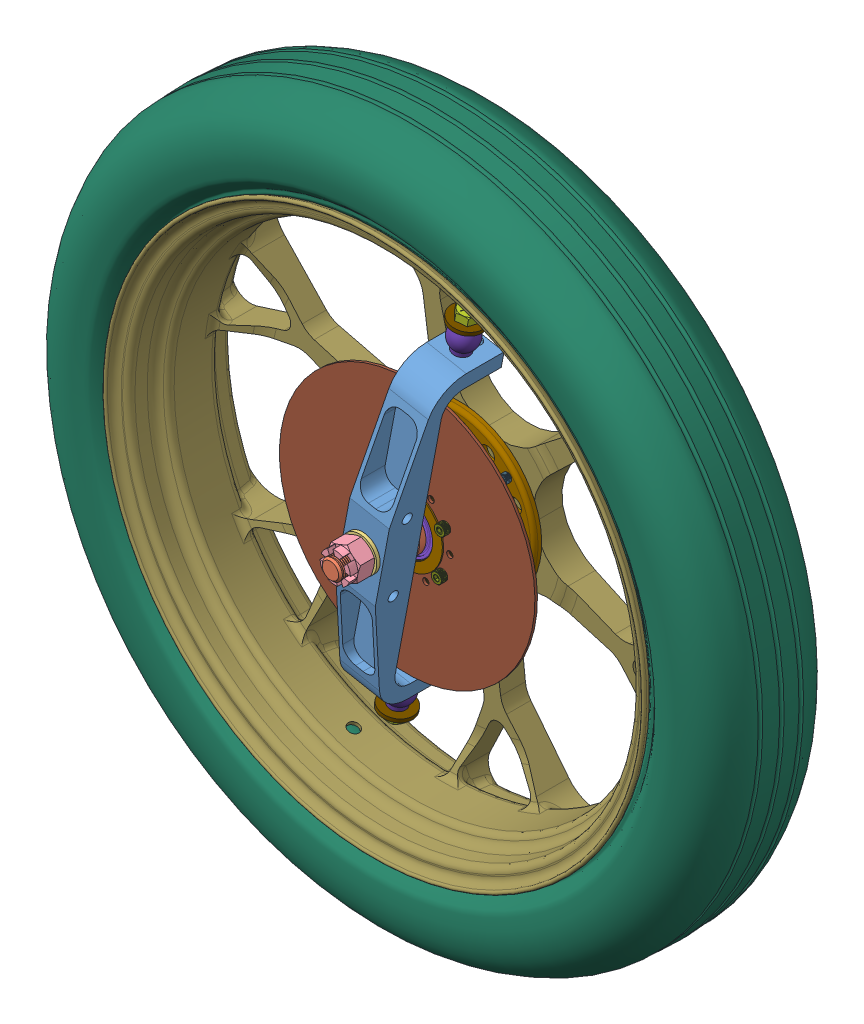
SolidWorks assembly SpindleAssy, configuration Default. Lengths in mm.
Overall size (616.2 616.2 145).
36 component instances, 18 part files, 73 mates.
Components (placement in the parent):
- Knuckle-1: Knuckle [Default] at (82.0121 130.0239 204.0915) size (78.12 253.33 73.5)
- Spindle_Light-1: Spindle_Light [Default] at (82.0121 130.0239 204.0915) x (0 0 -1) z (0.185408 0.982662 0) size (140.5 34 30)
- M16 98688A121_General Purpose Zinc-Plated Steel Washer-1: M16 98688A121_General Purpose Zinc-Plated Steel Washer [98688A121] at (82.0121 130.0239 232.5915) x (0.99983 -0.018445 0) z (0 0 1) size (28 28 2.7)
- M16x1-5 93760A128_Steel Locknut for Use with Cotter Pins-1: M16x1-5 93760A128_Steel Locknut for Use with Cotter Pins [93760A128] at (82.0121 130.0239 254.2915) x (0.982886 -0.184217 0) z (0 0 1) size (24 27.71 19.76)
- M14 98689A119_General Purpose 18-8 Stainless Steel Washer-1: M14 98689A119_General Purpose 18-8 Stainless Steel Washer [98689A119] at (82.0121 130.0239 138.2415) size (24 24 2.7)
- M14x1-5 93760A127_Steel Locknut for Use with Cotter Pins-1: M14x1-5 93760A127_Steel Locknut for Use with Cotter Pins [93760A127] at (82.0121 130.0239 120.8915) x (-0.661913 -0.74958 0) z (0 0 -1) size (22 25.4 16.76)
- 91257A659_Zinc Yellow-Chromate Plated Hex Head Screw-2: 91257A659_Zinc Yellow-Chromate Plated Hex Head Screw [91257A659] at (58.1191 3.3909 177.4439) x (0.185408 0.982662 0) z (0.110595 -0.020867 0.993646) size (57.6 16.5 14.29)
- 91257A659_Zinc Yellow-Chromate Plated Hex Head Screw-3: 91257A659_Zinc Yellow-Chromate Plated Hex Head Screw [91257A659] at (105.9051 256.6568 177.4439) x (-0.185408 -0.982662 0) z (-0.685297 0.129301 0.716693) size (57.6 16.5 14.29)
- SKF_6004-2Z.stp-1: SKF_6004-2Z.stp [Default] at (82.0121 130.0239 185.0915) x (0 0 1) z (-0.58163 0.813454 0) size (12 42 42)
- Hub5-16-1: Hub5-16 [Default] at (82.0121 130.0239 173.6746) x (-0.944813 0.32761 0) z (0.32761 0.944813 0) size (130 85 130)
- SKF_6003-2Z.stp-1: SKF_6003-2Z.stp [Default] at (82.0121 130.0239 149.5915) x (0 0 -1) z (0.973183 -0.230032 0) size (10 35 35)
- BasicBrakeDisc-1: BasicBrakeDisc [Default] at (82.0121 130.0239 195.0915) x (0.071911 0.997411 0) z (0 0 1) size (190.5 190.5 3.17)
- rimmachined v13.2-1: rimmachined v13.2 [Default] at (82.0121 130.0239 177.3915) x (0 0 -1) z (-0.981935 -0.189217 0) size (93.59 431.57 431.57)
- 92415A381_Zinc-Plated Steel Unthreaded Spacer-2: 92415A381_Zinc-Plated Steel Unthreaded Spacer [92415A381] at (71.0682 186.982 155.2387) size (7.94 7.94 7.21)
- 92415A381_Zinc-Plated Steel Unthreaded Spacer-3: 92415A381_Zinc-Plated Steel Unthreaded Spacer [92415A381] at (27.2129 149.0252 155.2387) size (7.94 7.94 7.21)
- 92415A381_Zinc-Plated Steel Unthreaded Spacer-4: 92415A381_Zinc-Plated Steel Unthreaded Spacer [92415A381] at (38.1569 92.0671 155.2387) size (7.94 7.94 7.21)
- 92415A381_Zinc-Plated Steel Unthreaded Spacer-5: 92415A381_Zinc-Plated Steel Unthreaded Spacer [92415A381] at (92.956 73.0657 155.2387) size (7.94 7.94 7.21)
- 92415A381_Zinc-Plated Steel Unthreaded Spacer-6: 92415A381_Zinc-Plated Steel Unthreaded Spacer [92415A381] at (136.8113 111.0225 155.2387) size (7.94 7.94 7.21)
- 92415A381_Zinc-Plated Steel Unthreaded Spacer-7: 92415A381_Zinc-Plated Steel Unthreaded Spacer [92415A381] at (125.8674 167.9807 155.2387) size (7.94 7.94 7.21)
- 8-32x3-8 92196A192_18-8 Stainless Steel Socket Head Screw-1: 8-32x3-8 92196A192_18-8 Stainless Steel Socket Head Screw [92196A192] at (92.956 73.0657 158.4118) size (6.85 6.85 14.15)
- 8-32x3-8 92196A192_18-8 Stainless Steel Socket Head Screw-2: 8-32x3-8 92196A192_18-8 Stainless Steel Socket Head Screw [92196A192] at (38.1569 92.0671 158.4118) size (6.85 6.85 14.15)
- 8-32x3-8 92196A192_18-8 Stainless Steel Socket Head Screw-3: 8-32x3-8 92196A192_18-8 Stainless Steel Socket Head Screw [92196A192] at (136.8113 111.0225 158.4118) size (6.85 6.85 14.15)
- 8-32x3-8 92196A192_18-8 Stainless Steel Socket Head Screw-4: 8-32x3-8 92196A192_18-8 Stainless Steel Socket Head Screw [92196A192] at (125.8674 167.9807 158.4118) size (6.85 6.85 14.15)
- 8-32x3-8 92196A192_18-8 Stainless Steel Socket Head Screw-5: 8-32x3-8 92196A192_18-8 Stainless Steel Socket Head Screw [92196A192] at (71.0682 186.982 158.4118) size (6.85 6.85 14.15)
- 8-32x3-8 92196A192_18-8 Stainless Steel Socket Head Screw-6: 8-32x3-8 92196A192_18-8 Stainless Steel Socket Head Screw [92196A192] at (27.2129 149.0252 158.4118) size (6.85 6.85 14.15)
- Michelin Tire-1: Michelin Tire [Default] at (82.0121 130.0239 177.3915) x (0 0 1) z (-0.993534 -0.113534 0) size (101.13 556.61 556.61)
- M5x10 91290A224_Alloy Steel Socket Head Screw-1: M5x10 91290A224_Alloy Steel Socket Head Screw [91290A224] at (84.4571 163.9358 194.5915) x (0.901899 0.431946 0) z (0 0 1) size (8.5 8.5 15.31)
- M5x10 91290A224_Alloy Steel Socket Head Screw-2: M5x10 91290A224_Alloy Steel Socket Head Screw [91290A224] at (53.866 149.0973 194.5915) x (-0.609316 -0.792927 0) z (0 0 1) size (8.5 8.5 15.31)
- M5x10 91290A224_Alloy Steel Socket Head Screw-3: M5x10 91290A224_Alloy Steel Socket Head Screw [91290A224] at (112.6032 144.8625 194.5915) x (0.740699 0.671837 0) z (0 0 1) size (8.5 8.5 15.31)
- M5x10 91290A224_Alloy Steel Socket Head Screw-4: M5x10 91290A224_Alloy Steel Socket Head Screw [91290A224] at (110.1583 110.9505 194.5915) x (-0.161403 -0.986889 0) z (0 0 1) size (8.5 8.5 15.31)
- M5x10 91290A224_Alloy Steel Socket Head Screw-5: M5x10 91290A224_Alloy Steel Socket Head Screw [91290A224] at (51.421 115.1853 194.5915) x (0.079005 -0.996874 0) z (0 0 1) size (8.5 8.5 15.31)
- M5x10 91290A224_Alloy Steel Socket Head Screw-6: M5x10 91290A224_Alloy Steel Socket Head Screw [91290A224] at (79.5671 96.1119 194.5915) x (-0.159143 -0.987256 0) z (0 0 1) size (8.5 8.5 15.31)
- BallSuper-Swivel  Joint Rod End6960T231_-1: BallSuper-Swivel  Joint Rod End6960T231_ [6960T231] at (75.3125 -8.1245 178.3098) x (-0.044663 0.008427 0.998967) z (-0.185408 -0.982662 0) size (20.64 20.64 22.23)
- BallSuper-Swivel  Joint Rod End6960T231_-2: BallSuper-Swivel  Joint Rod End6960T231_ [6960T231] at (109.0836 264.3285 196.4178) x (0.978736 -0.184667 -0.089292) z (0.185408 0.982662 0) size (20.64 20.64 22.23)
- 3-8 98029A046_Black-Oxide Steel Oversized Washer-1: 3-8 98029A046_Black-Oxide Steel Oversized Washer [98029A046] at (54.2751 -16.9823 177.4439) x (0.965511 -0.182172 -0.186017) z (0.185408 0.982662 0) size (25.4 25.4 2.98)
- 3-8 98029A046_Black-Oxide Steel Oversized Washer-2: 3-8 98029A046_Black-Oxide Steel Oversized Washer [98029A046] at (109.7491 277.0301 177.4439) x (0.965511 -0.182172 -0.186017) z (0.185408 0.982662 0) size (25.4 25.4 2.98)
Mates (geometry in assembly coordinates):
- Coincident1: coincident anti-aligned: circle of Knuckle-1; circle of Spindle_Light-1
- Concentric1: concentric aligned: circle of Knuckle-1; circle of M16 98688A121_General Purpose Zinc-Plated Steel Washer-1
- Concentric2: concentric aligned: circle of M16 98688A121_General Purpose Zinc-Plated Steel Washer-1; circle of M16x1-5 93760A128_Steel Locknut for Use with Cotter Pins-1
- Coincident2: coincident anti-aligned: plane of Knuckle-1 through (82.0121 130.0239 232.5915) normal (0 0 1); plane of M16 98688A121_General Purpose Zinc-Plated Steel Washer-1 through (82.0121 130.0239 232.5915) normal (0 0 -1)
- Coincident3: coincident anti-aligned: plane of M16 98688A121_General Purpose Zinc-Plated Steel Washer-1 through (82.0121 130.0239 235.2915) normal (0 0 1); plane of M16x1-5 93760A128_Steel Locknut for Use with Cotter Pins-1 through (84.5647 143.6431 235.2915) normal (0 0 -1)
- Parallel1: parallel aligned: plane of Spindle_Light-1 through (82.0121 130.0239 258.0915) normal (0 0 1); plane of M16x1-5 93760A128_Steel Locknut for Use with Cotter Pins-1 through (82.0121 130.0239 248.2915) normal (0 0 1)
- Concentric3: concentric anti-aligned: circle of M14 98689A119_General Purpose 18-8 Stainless Steel Washer-1; circle of M14x1-5 93760A127_Steel Locknut for Use with Cotter Pins-1
- Coincident5: coincident anti-aligned: plane of M14 98689A119_General Purpose 18-8 Stainless Steel Washer-1 through (82.0121 130.0239 136.8915) normal (0 0 -1); plane of M14x1-5 93760A127_Steel Locknut for Use with Cotter Pins-1 through (75.0117 150.8804 136.8915) normal (0 0 1)
- Concentric4: concentric anti-aligned: circle of Spindle_Light-1; circle of M14 98689A119_General Purpose 18-8 Stainless Steel Washer-1
- Perpendicular1: perpendicular: line of Knuckle-1 through (84.6232 230.1587 204.0915) axis (-0.185408 -0.982662 0); line of Spindle_Light-1 through (76.9319 146.2471 204.0915) axis (0.982662 -0.185408 0)
- Concentric5: concentric aligned: circle of Knuckle-1; circle of Super-Swivel Ball Joint Ball End2-1
- Coincident7: coincident anti-aligned: plane of Knuckle-1 through (89.6292 256.6906 232.5915) normal (0.185408 0.982662 0); plane of Super-Swivel Ball Joint Ball End2-1 through (107.5018 254.0508 172.0915) normal (-0.20131 -0.979528 0)
- Concentric6: concentric anti-aligned: circle of Knuckle-1; circle of Super-Swivel Ball Joint Ball End2-2
- Coincident8: coincident anti-aligned: plane of Knuckle-1 through (74.395 3.3572 232.5915) normal (-0.185408 -0.982662 0); plane of Super-Swivel Ball Joint Ball End2-2 through (56.5224 5.997 172.0915) normal (0.20131 0.979528 0)
- Coincident11: coincident anti-aligned: circle of Knuckle-1; circle of SteerArm-1
- Coincident12: coincident anti-aligned: circle of Knuckle-1; circle of SteerArm-1
- Concentric7: concentric anti-aligned: circle of Spindle_Light-1; circle of SKF_6004-2Z.stp-1
- Coincident13: coincident anti-aligned: plane of Spindle_Light-1 through (70.2202 132.2488 197.0915) normal (0 0 -1); plane of SKF_6004-2Z.stp-1 through (90.6347 136.1891 197.0915) normal (0 0 1)
- Coincident14: coincident anti-aligned: plane of SKF_6004-2Z.stp-1 through (98.6066 141.8891 185.0915) normal (0 0 -1); plane of Hub5-16-1 through (64.0607 136.2485 185.0915) normal (0 0 1)
- Concentric8: concentric aligned: cylinder of SKF_6004-2Z.stp-1 through (82.0121 130.0239 235.0915) axis (0 0 1) radius 21; cylinder of Hub5-16-1 through (82.0121 130.0239 1099.7023) axis (0 0 1) radius 21
- Concentric9: concentric anti-aligned: cylinder of Hub5-16-1 through (82.0121 130.0239 1099.7023) axis (0 0 1) radius 17.5; cylinder of SKF_6003-2Z.stp-1 through (82.0121 130.0239 99.5915) axis (0 0 -1) radius 17.5
- Coincident15: coincident anti-aligned: plane of Hub5-16-1 through (67.3675 135.1018 149.5915) normal (0 0 -1); plane of SKF_6003-2Z.stp-1 through (85.9687 146.7626 149.5915) normal (0 0 1)
- Coincident16: coincident anti-aligned: plane of M14 98689A119_General Purpose 18-8 Stainless Steel Washer-1 through (82.0121 130.0239 139.5915) normal (0 0 1); plane of SKF_6003-2Z.stp-1 through (84.0364 138.5879 139.5915) normal (0 0 -1)
- Concentric10: concentric aligned: circle of Hub5-16-1; circle of BasicBrakeDisc-1
- Coincident18: coincident anti-aligned: plane of Hub5-16-1 through (54.6125 139.5246 195.0915) normal (0 0 1); plane of BasicBrakeDisc-1 through (82.0121 130.0239 195.0915) normal (0 0 -1)
- Concentric11: concentric anti-aligned: cylinder of Hub5-16-1 through (82.0121 130.0239 1099.7023) axis (0 0 1) radius 47; cylinder of rimmachined v13.2-1 through (82.0121 130.0239 168.2915) axis (0 0 -1) radius 47.005
- Coincident19: coincident aligned: circle of Hub5-16-1; circle of 92415A381_Zinc-Plated Steel Unthreaded Spacer-5
- Coincident20: coincident aligned: circle of Hub5-16-1; circle of 92415A381_Zinc-Plated Steel Unthreaded Spacer-4
- Coincident21: coincident aligned: circle of Hub5-16-1; circle of 92415A381_Zinc-Plated Steel Unthreaded Spacer-3
- Coincident22: coincident aligned: circle of Hub5-16-1; circle of 92415A381_Zinc-Plated Steel Unthreaded Spacer-2
- Coincident23: coincident aligned: circle of Hub5-16-1; circle of 92415A381_Zinc-Plated Steel Unthreaded Spacer-7
- Coincident24: coincident aligned: circle of Hub5-16-1; circle of 92415A381_Zinc-Plated Steel Unthreaded Spacer-6
- Concentric121: concentric anti-aligned: cylinder of Hub5-16-1 through (92.956 73.0657 151.0915) axis (0 0 1) radius 2.15; cylinder of 8-32x3-8 92196A192_18-8 Stainless Steel Socket Head Screw-1 through (92.956 73.0657 151.5665) axis (0 0 -1) radius 2.0828
- Coincident251: coincident anti-aligned: plane of Hub5-16-1 through (23.4337 150.3357 161.0915) normal (0 0 1); plane of 8-32x3-8 92196A192_18-8 Stainless Steel Socket Head Screw-1 through (89.6985 73.0657 161.0915) normal (0 0 -1)
- Concentric131: concentric anti-aligned: cylinder of Hub5-16-1 through (38.1569 92.0671 151.0915) axis (0 0 1) radius 2.15; cylinder of 8-32x3-8 92196A192_18-8 Stainless Steel Socket Head Screw-2 through (38.1569 92.0671 151.5665) axis (0 0 -1) radius 2.0828
- Coincident261: coincident anti-aligned: plane of Hub5-16-1 through (23.4337 150.3357 161.0915) normal (0 0 1); plane of 8-32x3-8 92196A192_18-8 Stainless Steel Socket Head Screw-2 through (34.8993 92.0671 161.0915) normal (0 0 -1)
- Concentric141: concentric anti-aligned: cylinder of Hub5-16-1 through (136.8113 111.0225 151.0915) axis (0 0 1) radius 2.15; cylinder of 8-32x3-8 92196A192_18-8 Stainless Steel Socket Head Screw-3 through (136.8113 111.0225 151.5665) axis (0 0 -1) radius 2.0828
- Coincident271: coincident anti-aligned: plane of Hub5-16-1 through (23.4337 150.3357 161.0915) normal (0 0 1); plane of 8-32x3-8 92196A192_18-8 Stainless Steel Socket Head Screw-3 through (133.5537 111.0225 161.0915) normal (0 0 -1)
- Concentric151: concentric anti-aligned: cylinder of Hub5-16-1 through (125.8674 167.9807 151.0915) axis (0 0 1) radius 2.15; cylinder of 8-32x3-8 92196A192_18-8 Stainless Steel Socket Head Screw-4 through (125.8674 167.9807 151.5665) axis (0 0 -1) radius 2.0828
- Coincident281: coincident anti-aligned: plane of Hub5-16-1 through (23.4337 150.3357 161.0915) normal (0 0 1); plane of 8-32x3-8 92196A192_18-8 Stainless Steel Socket Head Screw-4 through (122.6098 167.9807 161.0915) normal (0 0 -1)
- Concentric161: concentric anti-aligned: cylinder of Hub5-16-1 through (71.0682 186.982 151.0915) axis (0 0 1) radius 2.15; cylinder of 8-32x3-8 92196A192_18-8 Stainless Steel Socket Head Screw-5 through (71.0682 186.982 151.5665) axis (0 0 -1) radius 2.0828
- Coincident291: coincident anti-aligned: plane of Hub5-16-1 through (23.4337 150.3357 161.0915) normal (0 0 1); plane of 8-32x3-8 92196A192_18-8 Stainless Steel Socket Head Screw-5 through (67.8106 186.982 161.0915) normal (0 0 -1)
- Concentric171: concentric anti-aligned: cylinder of Hub5-16-1 through (27.2129 149.0252 151.0915) axis (0 0 1) radius 2.15; cylinder of 8-32x3-8 92196A192_18-8 Stainless Steel Socket Head Screw-6 through (27.2129 149.0252 151.5665) axis (0 0 -1) radius 2.0828
- Coincident301: coincident anti-aligned: plane of Hub5-16-1 through (23.4337 150.3357 161.0915) normal (0 0 1); plane of 8-32x3-8 92196A192_18-8 Stainless Steel Socket Head Screw-6 through (23.9554 149.0252 161.0915) normal (0 0 -1)
- Tangent1: tangent anti-aligned: plane of rimmachined v13.2-1 through (88.5859 74.7696 150.7915) normal (0.981935 0.189217 0); cylinder of 92415A381_Zinc-Plated Steel Unthreaded Spacer-5 through (92.956 73.0657 151.6669) axis (0 0 1) radius 3.9688
- Coincident31: coincident anti-aligned: plane of Hub5-16-1 through (37.6059 145.4215 155.0915) normal (0 0 -1); plane of rimmachined v13.2-1 through (89.5808 90.7465 155.0915) normal (0 0 1)
- Concentric18: concentric aligned: cone of rimmachined v13.2-1 through (82.0121 130.0239 200.42) axis (0 0 -1); cylinder of Michelin Tire-1 through (82.0121 130.0239 74.6686) axis (0 0 -1) radius 203
- Coincident32: coincident anti-aligned: plane of rimmachined v13.2-1 through (82.0121 130.0239 177.3915) normal (0 0 -1); plane of Michelin Tire-1 through (82.0121 130.0239 177.3915) normal (0 0 1)
- Concentric19: concentric anti-aligned: cylinder of Hub5-16-1 through (67.1735 160.615 185.0915) axis (0 0 1) radius 2; cylinder of BasicBrakeDisc-1 through (67.1735 160.615 197.0915) axis (0 0 -1) radius 2.497
- Concentric20: concentric anti-aligned: circle of BasicBrakeDisc-1; circle of M5x10 91290A224_Alloy Steel Socket Head Screw-2
- Coincident33: coincident anti-aligned: plane of BasicBrakeDisc-1 through (82.0121 130.0239 197.0915) normal (0 0 1); plane of M5x10 91290A224_Alloy Steel Socket Head Screw-2 through (56.3032 152.269 197.0915) normal (0 0 -1)
- Concentric21: concentric anti-aligned: circle of BasicBrakeDisc-1; circle of M5x10 91290A224_Alloy Steel Socket Head Screw-1
- Concentric22: concentric anti-aligned: circle of BasicBrakeDisc-1; circle of M5x10 91290A224_Alloy Steel Socket Head Screw-3
- Concentric23: concentric anti-aligned: circle of BasicBrakeDisc-1; circle of M5x10 91290A224_Alloy Steel Socket Head Screw-4
- Concentric24: concentric anti-aligned: circle of BasicBrakeDisc-1; circle of M5x10 91290A224_Alloy Steel Socket Head Screw-6
- Concentric25: concentric anti-aligned: circle of BasicBrakeDisc-1; circle of M5x10 91290A224_Alloy Steel Socket Head Screw-5
- Coincident34: coincident anti-aligned: plane of BasicBrakeDisc-1 through (82.0121 130.0239 197.0915) normal (0 0 1); plane of M5x10 91290A224_Alloy Steel Socket Head Screw-1 through (80.8495 162.2081 197.0915) normal (0 0 -1)
- Coincident36: coincident anti-aligned: plane of BasicBrakeDisc-1 through (82.0121 130.0239 197.0915) normal (0 0 1); plane of M5x10 91290A224_Alloy Steel Socket Head Screw-3 through (109.6404 142.1751 197.0915) normal (0 0 -1)
- Coincident37: coincident anti-aligned: plane of BasicBrakeDisc-1 through (82.0121 130.0239 197.0915) normal (0 0 1); plane of M5x10 91290A224_Alloy Steel Socket Head Screw-5 through (51.105 119.1728 197.0915) normal (0 0 -1)
- Coincident38: coincident anti-aligned: plane of BasicBrakeDisc-1 through (82.0121 130.0239 197.0915) normal (0 0 1); plane of M5x10 91290A224_Alloy Steel Socket Head Screw-6 through (80.2037 100.0609 197.0915) normal (0 0 -1)
- Coincident39: coincident anti-aligned: plane of BasicBrakeDisc-1 through (82.0121 130.0239 197.0915) normal (0 0 1); plane of M5x10 91290A224_Alloy Steel Socket Head Screw-4 through (110.8039 114.898 197.0915) normal (0 0 -1)
- Coincident302: coincident anti-aligned: plane of Knuckle-1 through (89.6292 256.6906 232.5915) normal (0.185408 0.982662 0); plane of BallSuper-Swivel  Joint Rod End6960T231_-2 through (105.3518 253.724 177.4439) normal (-0.185408 -0.982662 0)
- Coincident303: coincident anti-aligned: plane of Knuckle-1 through (74.395 3.3572 232.5915) normal (-0.185408 -0.982662 0); plane of BallSuper-Swivel  Joint Rod End6960T231_-1 through (58.6725 6.3237 177.4439) normal (0.185408 0.982662 0)
- Concentric174: concentric aligned: cylinder of Knuckle-1 through (57.5915 0.5946 177.4439) axis (0.185408 0.982662 0) radius 4.7625; cylinder of BallSuper-Swivel  Joint Rod End6960T231_-2 through (105.4989 254.504 177.4439) axis (0.185408 0.982662 0) radius 4.7625
- Concentric175: concentric anti-aligned: cylinder of Knuckle-1 through (57.5915 0.5946 177.4439) axis (0.185408 0.982662 0) radius 4.7625; cylinder of BallSuper-Swivel  Joint Rod End6960T231_-1 through (58.5253 5.5437 177.4439) axis (-0.185408 -0.982662 0) radius 4.7625
- Concentric176: concentric anti-aligned: cylinder of 91257A659_Zinc Yellow-Chromate Plated Hex Head Screw-2 through (53.9984 -18.4487 177.4439) axis (0.185408 0.982662 0) radius 4.7625; cylinder of BallSuper-Swivel  Joint Rod End6960T231_-1 through (58.5253 5.5437 177.4439) axis (-0.185408 -0.982662 0) radius 4.7625
- Concentric177: concentric anti-aligned: cylinder of 91257A659_Zinc Yellow-Chromate Plated Hex Head Screw-2 through (53.9984 -18.4487 177.4439) axis (0.185408 0.982662 0) radius 4.7625; cylinder of 3-8 98029A046_Black-Oxide Steel Oversized Washer-1 through (54.5518 -15.516 177.4439) axis (-0.185408 -0.982662 0) radius 5.1562
- Coincident304: coincident anti-aligned: plane of BallSuper-Swivel  Joint Rod End6960T231_-1 through (54.5518 -15.516 177.4439) normal (-0.185408 -0.982662 0); plane of 3-8 98029A046_Black-Oxide Steel Oversized Washer-1 through (54.5518 -15.516 177.4439) normal (0.185408 0.982662 0)
- Coincident305: coincident anti-aligned: plane of 91257A659_Zinc Yellow-Chromate Plated Hex Head Screw-2 through (50.7613 -17.8379 185.0065) normal (0.185408 0.982662 0); plane of 3-8 98029A046_Black-Oxide Steel Oversized Washer-1 through (53.9984 -18.4487 177.4439) normal (-0.185408 -0.982662 0)
- Concentric178: concentric aligned: circle of BallSuper-Swivel  Joint Rod End6960T231_-2; circle of 3-8 98029A046_Black-Oxide Steel Oversized Washer-2
- Coincident306: coincident anti-aligned: plane of BallSuper-Swivel  Joint Rod End6960T231_-2 through (109.4725 275.5637 177.4439) normal (0.185408 0.982662 0); plane of 3-8 98029A046_Black-Oxide Steel Oversized Washer-2 through (109.4725 275.5637 177.4439) normal (-0.185408 -0.982662 0)
- Concentric179: concentric anti-aligned: cylinder of 91257A659_Zinc Yellow-Chromate Plated Hex Head Screw-3 through (110.0258 278.4965 177.4439) axis (-0.185408 -0.982662 0) radius 4.7625; cylinder of BallSuper-Swivel  Joint Rod End6960T231_-2 through (105.4989 254.504 177.4439) axis (0.185408 0.982662 0) radius 4.7625
- Coincident307: coincident anti-aligned: plane of 91257A659_Zinc Yellow-Chromate Plated Hex Head Screw-3 through (108.0349 278.8721 185.4402) normal (-0.185408 -0.982662 0); plane of 3-8 98029A046_Black-Oxide Steel Oversized Washer-2 through (110.0258 278.4965 177.4439) normal (0.185408 0.982662 0)
